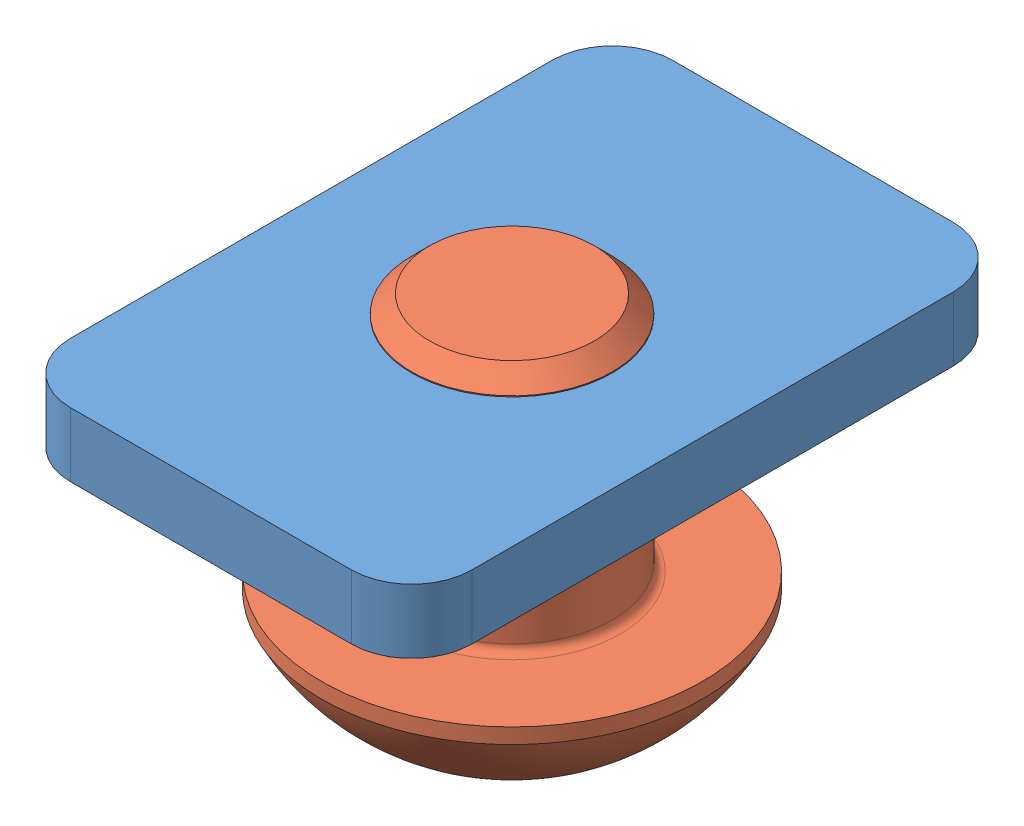
SolidWorks assembly BeltLocker, configuration По умолчанию. Lengths in mm.
Overall size (13.15 8.75 15).
2 component instances, 2 part files, 1 mates.
Components (placement in the parent):
- Square nut M5-1: Square nut M5 [Default] at (2.8297 0 3.7286) x (-1 0 0) z (0 0 1) size (10 3 15)
- head screw ISO 7380 M5 x 6-1: head screw ISO 7380 M5 x 6 [Default] at (2.8297 -8.281 3.7286) x (0 1 0) z (-0.546944 0 0.837169) size (8.75 9.5 9.5)
Mates (geometry in assembly coordinates):
- Концентричный1: concentric aligned: cylinder of Square nut M5-1 through (2.8297 -1.6 3.7286) axis (0 1 0) radius 2.5; cylinder of head screw ISO 7380 M5 x 6-1 through (2.8297 -11.9245 3.7286) axis (0 1 0) radius 2.5
